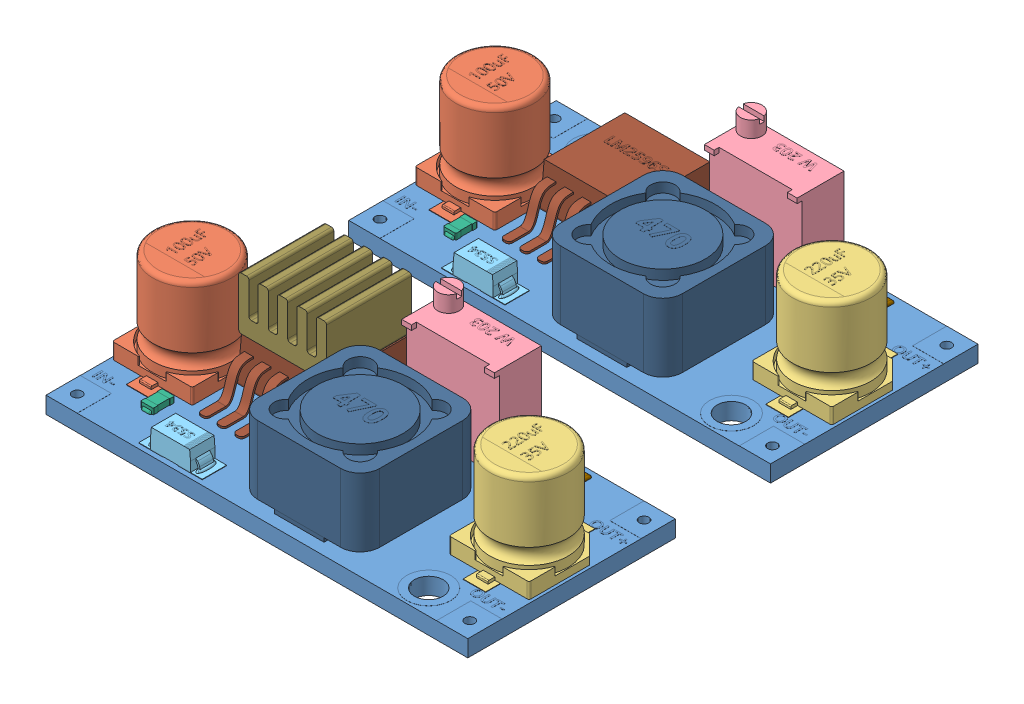
SolidWorks assembly LM2596 with and without cooler, configuration Default. Lengths in mm.
Overall size (43.2 15.15 52.25).
27 component instances, 12 part files, 3 mates.
Components (placement in the parent):
- converterLM2596-1: converterLM2596 [Default] at origin size (43.2 15.15 21.25)
  - lm2596board-1: lm2596board [Default] at origin size (43.2 1.71 21.25)
  - smd100uF-1: smd100uF [Default] at (-17.25 2.55 0) x (0 0 -1) z (1 0 0) size (11.2 9.76 8.2)
  - smd220uF-2: smd220uF [Default] at (17.25 2.55 0) x (0 0 -1) z (1 0 0) size (11.2 9.76 8.2)
  - TrimmerW203-1: TrimmerW203 [Default] at (4.6271 6.95 -9.1276) size (9.5 15.15 4.81)
  - smdS537diode-1: smdS537diode [Default] at (-9.35 1.75 8.875) x (-1 0 0) z (0 0 -1) size (6.5 2.13 2.5)
  - smdceramiccapacitor-1: smdceramiccapacitor [Default] at (-15 1.7 5.7969) x (0 0 1) z (-1 0 0) size (2.55 0.62 1.3)
  - smdceramiccapacitor-2: smdceramiccapacitor [Default] at (-1.3196 1.7 -5.2916) x (0 0 1) z (-1 0 0) size (2.55 0.62 1.3)
  - smdResistor331-1: smdResistor331 [Default] at (-1.2696 1.7 -8.4665) x (0 0 1) z (-1 0 0) size (2.54 0.62 1.34)
  - smdResistor102-1: smdResistor102 [Default] at (10.7771 1.7 -8.4665) x (0 0 -1) z (1 0 0) size (2.54 0.62 1.34)
  - smdLED-1: smdLED [Default] at (13.0521 1.75 -8.4701) x (0 0 -1) z (1 0 0) size (3.2 0.84 1.28)
  - smbInductor470-1: smbInductor470 [Default] at (3.1271 2.1 3.175) size (12.5 7.41 12.5)
  - LM2596S-1: LM2596S [Default] at (-8.0627 1.8 -4.5407) size (9.8 4.61 14.95)
- converterLM2596-2: converterLM2596 [Default] at (0 0 31.0041) size (43.2 15.15 21.25)
  - lm2596board-1: lm2596board [Default] at origin size (43.2 1.71 21.25)
  - smd100uF-1: smd100uF [Default] at (-17.25 2.55 0) x (0 0 -1) z (1 0 0) size (11.2 9.76 8.2)
  - smd220uF-2: smd220uF [Default] at (17.25 2.55 0) x (0 0 -1) z (1 0 0) size (11.2 9.76 8.2)
  - TrimmerW203-1: TrimmerW203 [Default] at (4.6271 6.95 -9.1276) size (9.5 15.15 4.81)
  - smdS537diode-1: smdS537diode [Default] at (-9.35 1.75 8.875) x (-1 0 0) z (0 0 -1) size (6.5 2.13 2.5)
  - smdceramiccapacitor-1: smdceramiccapacitor [Default] at (-15 1.7 5.7969) x (0 0 1) z (-1 0 0) size (2.55 0.62 1.3)
  - smdceramiccapacitor-2: smdceramiccapacitor [Default] at (-1.3196 1.7 -5.2916) x (0 0 1) z (-1 0 0) size (2.55 0.62 1.3)
  - smdResistor331-1: smdResistor331 [Default] at (-1.2696 1.7 -8.4665) x (0 0 1) z (-1 0 0) size (2.54 0.62 1.34)
  - smdResistor102-1: smdResistor102 [Default] at (10.7771 1.7 -8.4665) x (0 0 -1) z (1 0 0) size (2.54 0.62 1.34)
  - smdLED-1: smdLED [Default] at (13.0521 1.75 -8.4701) x (0 0 -1) z (1 0 0) size (3.2 0.84 1.28)
  - smbInductor470-1: smbInductor470 [Default] at (3.1271 2.1 3.175) size (12.5 7.41 12.5)
  - LM2596S-1: LM2596S [Default] at (-8.0627 1.8 -4.5407) size (9.8 4.61 14.95)
- IC Cooler-1: IC Cooler [Default] at (-8.2064 9 26.4384) size (9 5.4 8.7)
Mates (geometry in assembly coordinates):
- Coincident1: coincident anti-aligned: plane of converterLM2596-2/LM2596S-1 through (-8.0627 6.3 26.4634) normal (0 1 0); plane of IC Cooler-1 through (-12.7064 6.3 30.7884) normal (0 -1 0)
- Coincident2: coincident aligned: plane of converterLM2596-2/LM2596S-1 through (-12.8127 6.3 30.7884) normal (0 0 1); plane of IC Cooler-1 through (-8.2064 9 30.7884) normal (0 0 1)
- Coincident5: coincident: line of converterLM2596-2/LM2596S-1 through (-3.7064 6.3 30.7884) axis (0 0 -1); plane of IC Cooler-1 through (-3.7064 11.7 30.7884) normal (1 0 0)
